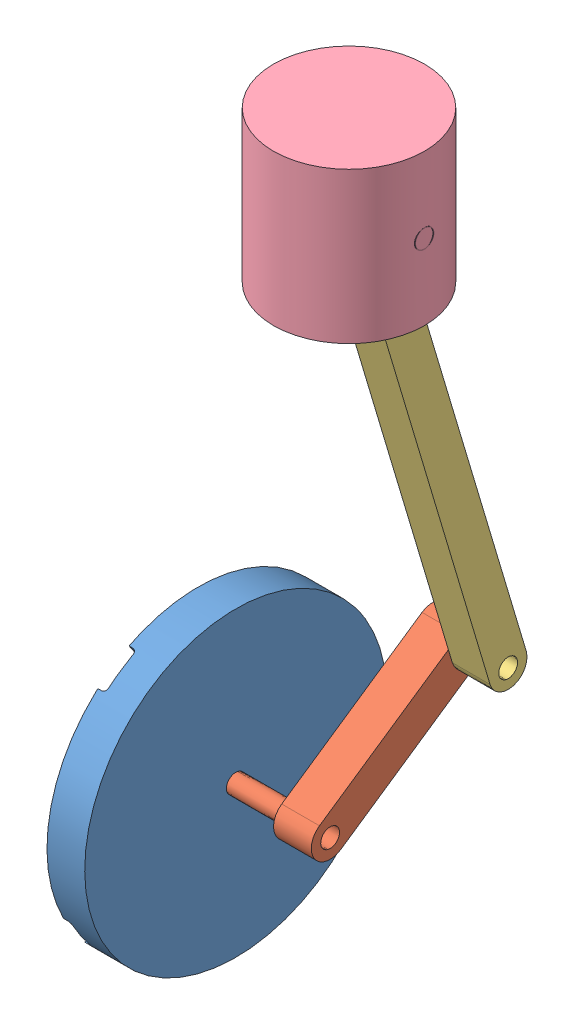
SolidWorks assembly cad_engine, configuration Default. Lengths in mm.
Overall size (60 225.54 111.18).
4 component instances, 4 part files, 10 mates.
Components (placement in the parent):
- flywheel-1: flywheel [Default] x (0 -0.825796 -0.563969) z (0 0.563969 -0.825796) size (80 10 80)
- crank-2: crank [Default] at (15 12.6893 -18.5804) x (0 -0.563969 0.825796) z (0 0.825796 0.563969) size (55 30 10)
- rod-2: rod [Default] at (25 87.6664 -18.5804) x (0 -0.958274 -0.285852) z (0 -0.285852 0.958274) size (140 10 10)
- head-2: head [Default] at (30 169.9542 0) x (1 0 0) z (0 0 -1) size (40 40 40)
Mates (geometry in assembly coordinates):
- Coincident1: coincident anti-aligned: plane of flywheel-1 through (0 0 0) normal (1 0 0); plane of crank-2 through (0 0 0) normal (-1 0 0)
- Concentric6: concentric anti-aligned: circle of flywheel-1; circle of crank-2
- Parallel1: parallel anti-aligned: line of flywheel-1 through (-10 6.9488 -1.3091) axis (0 0.563969 -0.825796); line of crank-2 through (15 29.5076 -34.341) axis (0 -0.563969 0.825796)
- Coincident3: coincident anti-aligned: plane of crank-2 through (25 25.3786 -37.1608) normal (1 0 0); plane of rod-2 through (25 149.9542 0) normal (-1 0 0)
- Coincident4: coincident anti-aligned: cylinder of crank-2 through (30 25.3786 -37.1608) axis (-1 0 0) radius 2.5; circle of rod-2
- Concentric8: concentric aligned: cylinder of rod-2 through (35 149.9542 0) axis (-1 0 0) radius 2.5; cylinder of head-2 through (50 149.9542 0) axis (-1 0 0) radius 2.5
- Coincident52: coincident anti-aligned: plane of head-2 through (30 169.9542 0) normal (0 0 -1); plane of assembly through (0 0 0) normal (0 0 1)
- Distance23: distance = 5 mm aligned: plane of rod-2; plane of head-2
- Coincident60: coincident: point of flywheel-1; point of assembly
- Coincident61: coincident anti-aligned: plane of flywheel-1; plane of assembly through (0 0 0) normal (1 0 0)
